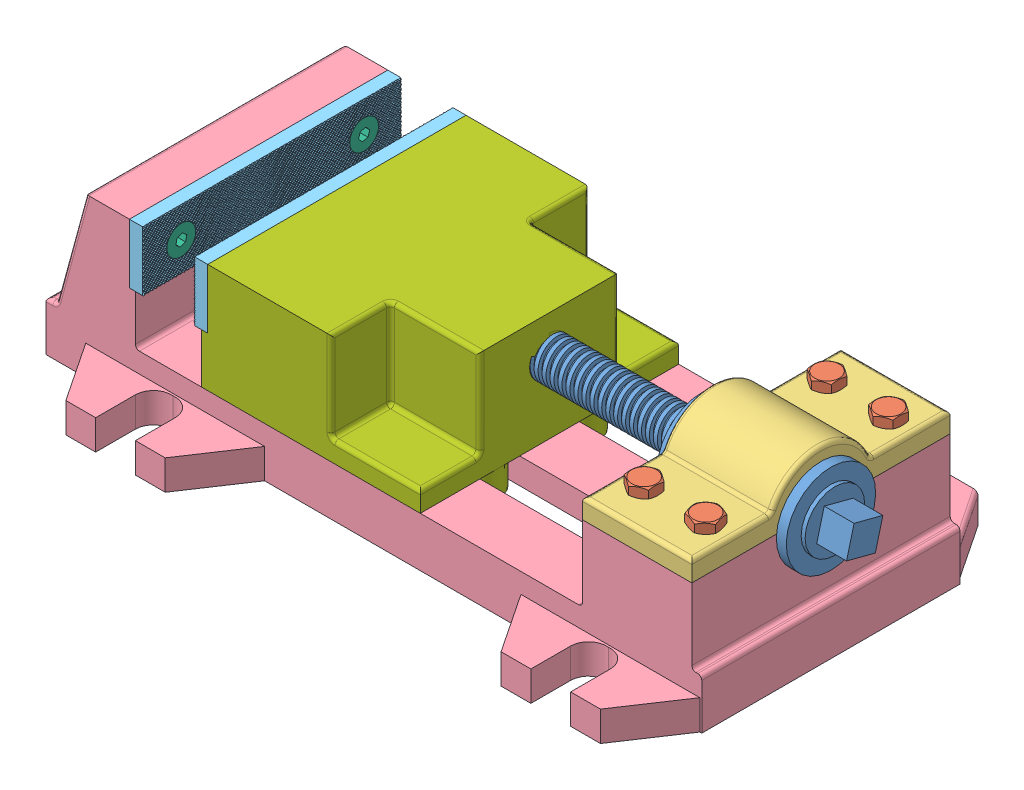
SolidWorks assembly Тиски - ЧМВ2.00.00, configuration По умолчанию. Lengths in mm.
Overall size (376.4 92.5 317.87).
20 component instances, 9 part files, 5 mates.
Components (placement in the parent):
- Основание - ЧМВ2.01.00-2: Основание - ЧМВ2.01.00 [По умолчанию] at origin size (376.4 90 317.87)
  - Вал - ЧМВ2.01.01-1: Вал - ЧМВ2.01.01 [По умолчанию] at (124.4504 77.8357 344.737) x (1 0 0) z (0 -0.252267 -0.967658) size (230 45 45)
  - Болт М20 - ЧМВ2.01.03-1: Болт М20 - ЧМВ2.01.03 [По умолчанию] at (174.4504 95.1357 390.737) x (-0.837169 0 -0.546944) z (-0.546944 0 0.837169) size (15.01 28.64 13)
  - Болт М20 - ЧМВ2.01.03-2: Болт М20 - ЧМВ2.01.03 [По умолчанию] at (205.4504 95.1357 390.737) x (-0.954672 0 -0.29766) z (-0.29766 0 0.954672) size (15.01 28.64 13)
  - Болт М20 - ЧМВ2.01.03-3: Болт М20 - ЧМВ2.01.03 [По умолчанию] at (205.4504 95.1357 298.737) x (-0.837169 0 -0.546944) z (-0.546944 0 0.837169) size (15.01 28.64 13)
  - Болт М20 - ЧМВ2.01.03-4: Болт М20 - ЧМВ2.01.03 [По умолчанию] at (174.4504 95.1357 298.737) x (-0.837169 0 -0.546944) z (-0.546944 0 0.837169) size (15.01 28.64 13)
  - Крышка - ЧМВ2.01.02-1: Крышка - ЧМВ2.01.02 [По умолчанию] at (217.4504 79.8357 344.737) x (0 0 1) z (-1 0 0) size (130 27 55)
  - Основа тисков - ЧМВ2.01.01-1: Основа тисков - ЧМВ2.01.01 [По умолчанию] at (32.9367 66.0161 279.737) size (376.4 80 317.87)
  - Губки для тисков - ЧМВ2.03.01-3: Губки для тисков - ЧМВ2.03.01 [По умолчанию] at (-65.5496 81.8357 344.737) x (0 0 -1) z (1 0 0) size (130 30 7.06)
  - Винт М8 - ЧМВ2.03.02-3: Винт М8 - ЧМВ2.03.02 [По умолчанию] at (-58.4596 81.8357 390.737) x (0 0.782667 0.622441) z (1 0 0) size (14.5 14.5 20)
  - Винт М8 - ЧМВ2.03.02-4: Винт М8 - ЧМВ2.03.02 [По умолчанию] at (-58.4596 81.8357 298.737) x (0 -0.851898 -0.523708) z (1 0 0) size (14.5 14.5 20)
- Подвижная часть - ЧМВ2.02.00-2: Подвижная часть - ЧМВ2.02.00 [По умолчанию] at (4.3584 0 0) size (116.09 82.5 130)
  - Подвижная часть ред. - ЧМВ2.02.01-1: Подвижная часть ред. - ЧМВ2.02.01 [По умолчанию] at (21.4678 41.8357 344.737) size (112 68 130)
  - Шайба - ЧМВ2.02.03-1: Шайба - ЧМВ2.02.03 [По умолчанию] at (21.4678 26.8357 369.737) x (0.999511 0 -0.031261) z (0.031261 0 0.999511) size (35 2 35)
  - Шайба - ЧМВ2.02.03-2: Шайба - ЧМВ2.02.03 [По умолчанию] at (21.4678 26.8357 319.737) x (0.013506 0 -0.999909) z (0.999909 0 0.013506) size (35 2 35)
  - Болт М8 - ЧМВ2.02.02-1: Болт М8 - ЧМВ2.02.02 [По умолчанию] at (21.4678 14.3357 369.737) x (0.22437 0 0.974504) z (-0.974504 0 0.22437) size (30 58.5 25.98)
  - Болт М8 - ЧМВ2.02.02-2: Болт М8 - ЧМВ2.02.02 [По умолчанию] at (21.4678 14.3357 319.737) x (0.783213 0 -0.621753) z (0.621753 0 0.783213) size (30 58.5 25.98)
  - Винт М8 - ЧМВ2.03.02-3: Винт М8 - ЧМВ2.03.02 [По умолчанию] at (-37.6222 81.8357 298.737) x (0 0.266843 0.96374) z (-1 0 0) size (14.5 14.5 20)
  - Винт М8 - ЧМВ2.03.02-4: Винт М8 - ЧМВ2.03.02 [По умолчанию] at (-37.6222 81.8357 390.737) x (0 0.506287 0.862365) z (-1 0 0) size (14.5 14.5 20)
  - Губки для тисков - ЧМВ2.03.01-2: Губки для тисков - ЧМВ2.03.01 [По умолчанию] at (-30.5322 81.8357 344.737) x (0 0 1) z (-1 0 0) size (130 30 7.06)
Mates (geometry in assembly coordinates):
- Совпадение73: coincident anti-aligned: plane of Основание - ЧМВ2.01.00-2/Основа тисков - ЧМВ2.01.01-1 through (162.4504 41.8357 409.737) normal (0 1 0); plane of Подвижная часть - ЧМВ2.02.00-2/Подвижная часть ред. - ЧМВ2.02.01-1 through (25.8263 41.8357 344.737) normal (0 -1 0)
- Совпадение74: coincident anti-aligned: plane of Основание - ЧМВ2.01.00-2/Основа тисков - ЧМВ2.01.01-1 through (-27.5496 16.8357 309.737) normal (0 0 1); plane of Подвижная часть - ЧМВ2.02.00-2/Подвижная часть ред. - ЧМВ2.02.01-1 through (70.8263 28.8357 309.737) normal (0 0 -1)
- Совпадение76: coincident anti-aligned: plane of Основание - ЧМВ2.01.00-2/Основа тисков - ЧМВ2.01.01-1 through (32.9367 28.8357 279.737) normal (0 -1 0); plane of Подвижная часть - ЧМВ2.02.00-2/Шайба - ЧМВ2.02.03-2 through (25.8263 28.8357 319.737) normal (0 1 0)
- Граничное расстояние2: limit distance = 76.6241 mm anti-aligned: plane of Подвижная часть - ЧМВ2.02.00-2/Подвижная часть ред. - ЧМВ2.02.01-1 through (80.8263 96.8357 409.737) normal (1 0 0); plane of Основание - ЧМВ2.01.00-2/Вал - ЧМВ2.01.01-1 through (157.4504 68.1591 347.2597) normal (-1 0 0)
- Совпадение77: coordinate: point of Основание - ЧМВ2.01.00-2
